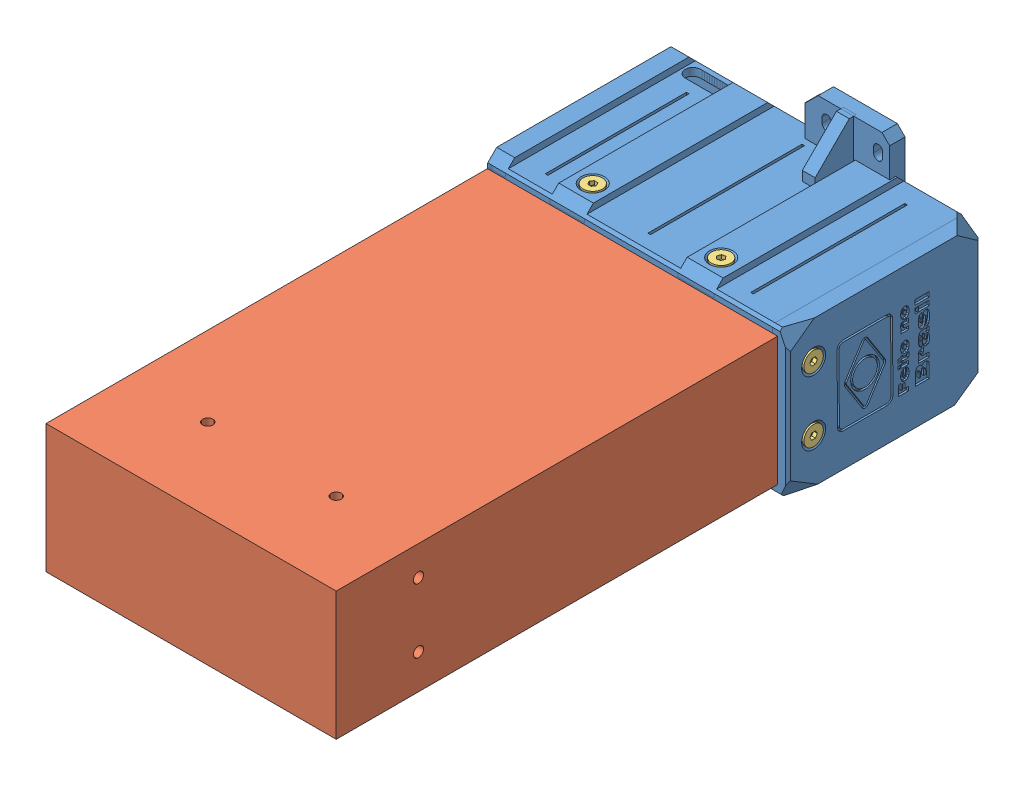
SolidWorks assembly Assembly psu, configuration Valor predeterminado. Lengths in mm.
Overall size (117 80.5 246.9).
13 component instances, 7 part files, 28 mates.
Components (placement in the parent):
- psu-cover-1: psu-cover [Valor predeterminado] at (-54.1692 22.2532 79.5) size (117 76 75)
- Power supply - 12V 30A-1: Power supply - 12V 30A [Valor predeterminado] at (-55.1692 -4.7468 218.9) x (0 1 0) z (1 0 0) size (50 215 113)
- Screw DIN 7991 - M4 x 10 --- 10N-1: Screw DIN 7991 - M4 x 10 --- 10N [Valor predeterminado] at (61.8308 -16.2468 144.5) size (10 7.53 7.53)
- Screw DIN 7991 - M4 x 10 --- 10N-2: Screw DIN 7991 - M4 x 10 --- 10N [Valor predeterminado] at (61.8308 8.7532 144.5) size (10 7.53 7.53)
- Screw DIN 7991 - M4 x 10 --- 10N-3: Screw DIN 7991 - M4 x 10 --- 10N [Valor predeterminado] at (-24.1692 25.7532 144.5) x (0 1 0) z (0.450605 0 0.892724) size (10 7.53 7.53)
- Screw DIN 7991 - M4 x 10 --- 10N-4: Screw DIN 7991 - M4 x 10 --- 10N [Valor predeterminado] at (25.8308 25.7532 144.5) x (0 1 0) z (-0.974607 0 0.223922) size (10 7.53 7.53)
- AC Power Connector - IEC C14 -1: AC Power Connector - IEC C14  [Valor predeterminado] at (25.8308 -36.7468 95.5) x (1 0 0) z (0 -1 0) size (50 22.4 26.9)
- Nut DIN 934 - M3-1: Nut DIN 934 - M3 [Valor predeterminado] at (5.8308 -30.7468 95.5) x (0 1 0) z (-0.5 0 0.866025) size (2.4 5.5 6.35)
- Nut DIN 934 - M3-3: Nut DIN 934 - M3 [Valor predeterminado] at (45.8308 -30.7468 95.5) x (0 1 0) z (-1 0 0) size (2.4 5.5 6.35)
- Screw DIN 912 - M3 x 10 --- 10N-1: Screw DIN 912 - M3 x 10 --- 10N [Valor predeterminado] at (5.8308 -40.2468 95.5) x (0 -1 0) z (-0.982094 0 -0.188394) size (13 5.5 5.5)
- Washer DIN 125A - M3-1: Washer DIN 125A - M3 [Valor predeterminado] at (5.8308 -36.7468 95.5) x (0 -1 0) z (0.838676 0 0.544631) size (0.5 7 7)
- Washer DIN 125A - M3-2: Washer DIN 125A - M3 [Valor predeterminado] at (45.8308 -36.7468 95.5) x (0 -1 0) z (0.065 0 0.997885) size (0.5 7 7)
- Screw DIN 912 - M3 x 10 --- 10N-2: Screw DIN 912 - M3 x 10 --- 10N [Valor predeterminado] at (45.8308 -40.2468 95.5) x (0 -1 0) z (-0.934431 0 0.356145) size (13 5.5 5.5)
Mates (geometry in assembly coordinates):
- Coincidente1: coincident: plane of assembly; plane of assembly; plane of psu-cover-1 through (57.8308 20.2532 128.1) normal (-1 0 0); plane of Power supply - 12V 30A-1 through (57.8308 -4.7468 218.9) normal (1 0 0)
- Coincidente2: coincident: plane of assembly; plane of assembly; plane of psu-cover-1 through (-51.1692 20.2532 81.5) normal (0 -1 0); plane of Power supply - 12V 30A-1 through (57.8308 20.2532 326.4) normal (0 1 0)
- Coincidente3: coincident: plane of assembly; plane of assembly; plane of psu-cover-1 through (47.8308 20.2532 111.4) normal (0 0 1); plane of Power supply - 12V 30A-1 through (57.8308 -29.7468 111.4) normal (0 0 -1)
- Concêntrico1: concentric: cylinder of assembly; cylinder of assembly; cylinder of psu-cover-1 through (90.8308 -16.2468 144.5) axis (-1 0 0) radius 2.5; cylinder of Screw DIN 7991 - M4 x 10 --- 10N-1 through (61.8308 -16.2468 144.5) axis (1 0 0) radius 2
- Coincidente4: coincident: plane of assembly; plane of assembly; plane of psu-cover-1 through (61.8308 23.2532 79.5) normal (1 0 0); plane of Screw DIN 7991 - M4 x 10 --- 10N-1 through (61.8308 -16.2468 144.5) normal (1 0 0)
- Concêntrico3: concentric: cylinder of assembly; cylinder of assembly; cylinder of psu-cover-1 through (90.8308 8.7532 144.5) axis (-1 0 0) radius 2.5; cylinder of Screw DIN 7991 - M4 x 10 --- 10N-2 through (61.8308 8.7532 144.5) axis (1 0 0) radius 2
- Coincidente5: coincident: plane of assembly; plane of assembly; plane of psu-cover-1 through (61.8308 23.2532 79.5) normal (1 0 0); plane of Screw DIN 7991 - M4 x 10 --- 10N-2 through (61.8308 8.7532 144.5) normal (1 0 0)
- Concêntrico4: concentric: cylinder of assembly; cylinder of assembly; cylinder of psu-cover-1 through (-24.1692 32.2532 144.5) axis (0 -1 0) radius 2.5; cylinder of Screw DIN 7991 - M4 x 10 --- 10N-3 through (-24.1692 25.7532 144.5) axis (0 1 0) radius 2
- Coincidente6: coincident: plane of assembly; plane of assembly; plane of psu-cover-1 through (-30.9192 25.7532 79.5) normal (0 1 0); plane of Screw DIN 7991 - M4 x 10 --- 10N-3 through (-24.1692 25.7532 144.5) normal (0 1 0)
- Concêntrico5: concentric: cylinder of assembly; cylinder of assembly; cylinder of psu-cover-1 through (25.8308 32.2532 144.5) axis (0 -1 0) radius 2.5; cylinder of Screw DIN 7991 - M4 x 10 --- 10N-4 through (25.8308 25.7532 144.5) axis (0 1 0) radius 2
- Coincidente7: coincident: plane of assembly; plane of assembly; plane of psu-cover-1 through (19.0808 25.7532 79.5) normal (0 1 0); plane of Screw DIN 7991 - M4 x 10 --- 10N-4 through (25.8308 25.7532 144.5) normal (0 1 0)
- Coincidente8: coincident: plane of assembly; plane of assembly; plane of psu-cover-1 through (25.8308 22.2532 79.5) normal (1 0 0); plane of AC Power Connector - IEC C14 -1 through (25.8308 -36.7468 95.5) normal (1 0 0)
- Coincidente9: coincident: plane of assembly; plane of assembly; plane of psu-cover-1 through (-54.1692 22.2532 95.5) normal (0 0 1); plane of AC Power Connector - IEC C14 -1 through (25.8308 -36.7468 95.5) normal (0 0 1)
- Coincidente10: coincident: plane of assembly; plane of assembly; plane of psu-cover-1 through (-54.1692 -33.4468 79.5) normal (0 -1 0); plane of AC Power Connector - IEC C14 -1 through (25.8308 -33.4468 95.5) normal (0 1 0)
- Concêntrico6: concentric: cylinder of assembly; cylinder of assembly; cylinder of psu-cover-1 through (5.8308 -18.4468 95.5) axis (0 -1 0) radius 1.75; cylinder of Nut DIN 934 - M3-1 through (5.8308 -29.5468 95.5) axis (0 -1 0) radius 1.25
- Paralelo1: parallel: plane of assembly; plane of assembly; plane of psu-cover-1 through (2.5808 -18.4468 95.5) normal (0.866025 0 0.5); plane of Nut DIN 934 - M3-1 through (7.4185 -29.5468 98.25) normal (0.866025 0 0.5)
- Coincidente12: coincident: plane of assembly; plane of assembly; plane of psu-cover-1 through (5.8308 -31.9468 95.5) normal (0 1 0); plane of Nut DIN 934 - M3-1 through (9.0062 -31.9468 95.5) normal (0 -1 0)
- Concêntrico8: concentric: cylinder of assembly; cylinder of assembly; cylinder of psu-cover-1 through (45.8308 -18.4468 95.5) axis (0 -1 0) radius 1.75; cylinder of Nut DIN 934 - M3-3 through (45.8308 -29.5468 95.5) axis (0 -1 0) radius 1.25
- Paralelo2: parallel: plane of assembly; plane of assembly; plane of psu-cover-1 through (44.2058 -18.4468 92.6854) normal (0 0 1); plane of Nut DIN 934 - M3-3 through (44.2431 -29.5468 98.25) normal (0 0 1)
- Coincidente14: coincident: plane of assembly; plane of assembly; plane of psu-cover-1 through (45.8308 -31.9468 95.5) normal (0 1 0); plane of Nut DIN 934 - M3-3 through (47.4185 -31.9468 98.25) normal (0 -1 0)
- Concêntrico9: concentric: cylinder of assembly; cylinder of assembly; cylinder of Screw DIN 912 - M3 x 10 --- 10N-1 through (5.8308 -40.2468 95.5) axis (0 -1 0) radius 1.5; cylinder of Washer DIN 125A - M3-1 through (5.8308 -37.2468 95.5) axis (0 1 0) radius 1.6
- Coincidente15: coincident: plane of assembly; plane of assembly; plane of Screw DIN 912 - M3 x 10 --- 10N-1 through (5.3127 -37.2468 98.2008) normal (0 1 0); plane of Washer DIN 125A - M3-1 through (5.8308 -37.2468 95.5) normal (0 -1 0)
- Coincidente16: coincident: plane of assembly; plane of assembly; plane of Washer DIN 125A - M3-2 through (45.8308 -37.2468 95.5) normal (0 -1 0); plane of Screw DIN 912 - M3 x 10 --- 10N-2 through (46.8102 -37.2468 98.0697) normal (0 1 0)
- Concêntrico10: concentric: cylinder of assembly; cylinder of assembly; cylinder of Washer DIN 125A - M3-2 through (45.8308 -37.2468 95.5) axis (0 1 0) radius 1.6; cylinder of Screw DIN 912 - M3 x 10 --- 10N-2 through (45.8308 -40.2468 95.5) axis (0 -1 0) radius 1.5
- Concêntrico11: concentric: cylinder of assembly; cylinder of assembly; cylinder of Nut DIN 934 - M3-1 through (5.8308 -29.5468 95.5) axis (0 -1 0) radius 1.25; cylinder of Screw DIN 912 - M3 x 10 --- 10N-1 through (5.8308 -40.2468 95.5) axis (0 -1 0) radius 1.5
- Coincidente17: coincident: plane of assembly; plane of assembly; plane of AC Power Connector - IEC C14 -1 through (25.8308 -36.7468 95.5) normal (0 -1 0); plane of Washer DIN 125A - M3-1 through (5.8308 -36.7468 95.5) normal (0 1 0)
- Concêntrico12: concentric: cylinder of assembly; cylinder of assembly; cylinder of Nut DIN 934 - M3-3 through (45.8308 -29.5468 95.5) axis (0 -1 0) radius 1.25; cylinder of Screw DIN 912 - M3 x 10 --- 10N-2 through (45.8308 -40.2468 95.5) axis (0 -1 0) radius 1.5
- Coincidente18: coincident: plane of assembly; plane of assembly; plane of AC Power Connector - IEC C14 -1 through (25.8308 -36.7468 95.5) normal (0 -1 0); plane of Washer DIN 125A - M3-2 through (45.8308 -36.7468 95.5) normal (0 1 0)
